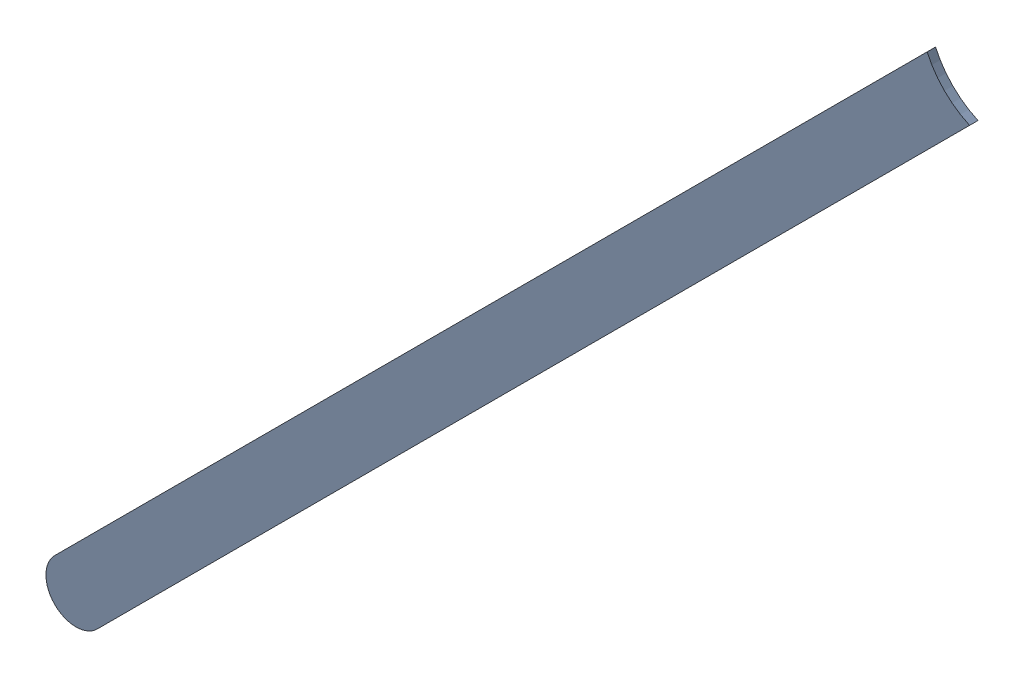
SolidWorks assembly Track (20.574mm,54.574mm)(24.5mm,58.5mm) on Bottom Layer, configuration Predeterminado. Lengths in mm.
Overall size (3.91 3.91 0.04).
2 component instances, 1 part files, 0 mates.
Components (placement in the parent):
- Track (20.574mm,54.574mm)(24.5mm,58.5mm) on Bottom Layer-1-1: Track (20.574mm,54.574mm)(24.5mm,58.5mm) on Bottom Layer-1 [Predeterminado] at (-68.317 -44.187 -0.4013) size (3.91 3.91 0.04)
  - Track (20.574mm,54.574mm)(24.5mm,58.5mm) on Bottom Layer-Part-1-1: Track (20.574mm,54.574mm)(24.5mm,58.5mm) on Bottom Layer-Part-1 [Predeterminado] at origin size (3.91 3.91 0.04)
